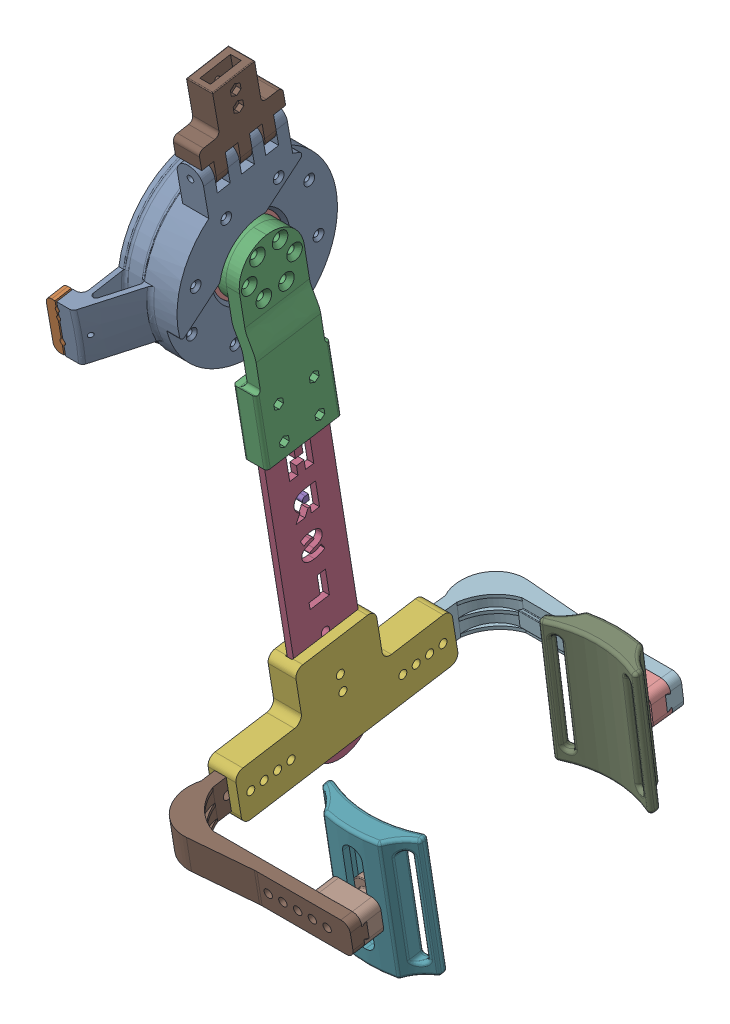
SolidWorks assembly FullExoAssemL_v1, configuration Default. Lengths in mm.
Overall size (178.34 419.53 240.88).
16 component instances, 11 part files, 31 mates.
Components (placement in the parent):
- MotorHousingL_v3-1: MotorHousingL_v3 [Default] at (44.6941 57.478 113.8206) x (0 0.171627 -0.985162) z (1 0 0) size (136.17 126 49)
- RotorAttachCanted_v4_hinge_removed_8mm-1: RotorAttachCanted_v4_hinge_removed_8mm [Default] at (27.6941 57.478 113.8206) x (0 0.15992 -0.98713) z (1 0 0) size (46.2 119 18)
- ThighHinge-1: ThighHinge [Default] at (32.9361 -19.972 124.8736) x (0 -0.113584 -0.993528) z (-0.995056 0.098671 -0.01128) (suppressed, hidden)
- ThighVertAdjust_v1-1: ThighVertAdjust_v1 [Default] at (38.4941 -223.3605 68.3234) x (0 0.15992 -0.98713) z (1 0 0) size (40 225 4)
- ThighTShape_v2-1: ThighTShape_v2 [Default] at (29.6941 -182.6608 75.4235) x (0 0.15992 -0.98713) z (1 0 0) size (134 60 17)
- sliding_mechanism-1: sliding_mechanism [Default] at (171.3989 -236.2303 143.4184) x (-0.99997 0.007656 0.00124) z (0 0.15992 -0.98713) size (60 80 31.83)
  - slide1-2: slide1 [Default] at (35.9132 -9.9128 77.9746) size (60 80 19.04)
  - slide2_centered-2: slide2_centered [Default] at (35.9132 26.7329 3.1866) x (-1 0 0) z (0 0 -1) size (30 20 23)
- sliding_mechanism-2: sliding_mechanism [Default] at (99.5809 -212.8167 -5.0848) x (1 0 0) z (0 -0.122171 0.992509) size (60 80 31.83)
  - slide1-2: slide1 [Default] at (35.9132 -9.9128 77.9746) size (60 80 19.04)
  - slide2_centered-2: slide2_centered [Default] at (35.9132 26.7329 3.1866) x (-1 0 0) z (0 0 -1) size (30 20 23)
- MotorHipAttach-2: MotorHipAttach [Default] at (29.6214 115.3141 117.118) x (0 0 1) z (-0.997763 0.066849 0) (suppressed, hidden)
- Lshape-thigh-3: Lshape-thigh [Default] at (150.6941 -223.7106 172.5083) x (-1 0 0) z (0 0.15992 -0.98713) size (119.06 20 70.06)
- Lshape-thigh-4: Lshape-thigh [Default] at (150.4941 -173.0954 -27.1104) x (-1 0 0) z (0 -0.122171 0.992509) size (119.06 20 70.06)
- AK80-95_-1: AK80-95_ [默认] at (756.7796 -361.1379 390.1752) x (-1 0 0) z (0 -0.550937 -0.834547) size (38.51 98 98)
- Upper_hinge_orthosis_modified-1: Upper_hinge_orthosis_modified [Default] at (28.6941 121.5928 124.5214) x (0 0.171627 -0.985162) z (1 0 0) size (52 53 16)
Mates (geometry in assembly coordinates):
- Concentric1: concentric aligned: cone of MotorHousingL_v3-1 through (26.6941 57.478 113.8206) axis (-1 0 0); cylinder of RotorAttachCanted_v4_hinge_removed_8mm-1 through (33.6941 57.478 113.8206) axis (-1 0 0) radius 20
- Coincident2: coincident anti-aligned: plane of RotorAttachCanted_v2-1 through (36.6214 -11.4544 139.8027) normal (0 -0.113584 -0.993528); plane of ThighHinge-1 through (41.5917 -12.0464 139.8704) normal (0 0.113584 0.993528)
- Concentric2: concentric anti-aligned: circle of RotorAttachCanted_v2-1; circle of ThighHinge-1
- Coincident3: coincident anti-aligned: plane of ThighVertAdjust_v1-1 through (36.4941 -4.4547 124.048) normal (-1 0 0); plane of ThighHinge-1 through (30.051 -24.987 105.0147) normal (0.995056 -0.098671 0.01128)
- Coincident4: coincident anti-aligned: plane of ThighHinge-1 through (32.6382 -22.9378 125.2126) normal (-0.099313 -0.988617 0.113022); plane of ThighVertAdjust_v1-1 through (38.4941 -1.2563 104.3054) normal (0 0.98713 0.15992)
- Coincident5: coincident anti-aligned: plane of ThighHinge-1 through (30.051 -24.987 105.0147) normal (0 0.113584 0.993528); plane of ThighVertAdjust_v1-1 through (36.4941 1.9421 84.5628) normal (0 0.15992 -0.98713)
- Coincident6: coincident anti-aligned: plane of ThighVertAdjust_v1-1 through (36.4941 -4.4547 124.048) normal (-1 0 0); plane of ThighTShape_v2-1 through (36.4941 -215.553 90.8621) normal (1 0 0)
- Coincident8: coincident anti-aligned: plane of MotorHousingL_v3-1 through (20.6941 126.1339 145.0674) normal (0 0.171627 -0.985162); plane of MotorHipAttach-1 through (21.6214 106.3141 135.6369) normal (0 0 1)
- Concentric3: concentric aligned: circle of MotorHousingL_v3-1; circle of MotorHipAttach-1
- Coincident21: coincident anti-aligned: plane of MotorHousingL_v3-1 through (20.6941 126.1339 145.0674) normal (0 0.171627 -0.985162); plane of MotorHipAttach-2 through (37.0019 105.7994 135.6369) normal (0 0 1)
- Concentric6: concentric aligned: circle of MotorHousingL_v3-1; circle of MotorHipAttach-2
- Coincident23: coincident anti-aligned: plane of ThighTShape_v2-1 through (40.6941 -191.5145 98.8086) normal (-1 0 0); plane of Lshape-thigh-3 through (40.6941 -199.6502 149.0542) normal (1 0 0)
- Parallel2: parallel aligned: plane of sliding_mechanism-1/slide2_centered-2 through (150.7344 -207.1727 165.0572) normal (0 -0.15992 0.98713); plane of Lshape-thigh-3 through (150.6941 -203.968 175.7067) normal (0 -0.15992 0.98713)
- Coincident26: coincident anti-aligned: plane of RotorAttachCanted_v4_hinge_removed_8mm-1 through (36.4941 2.4837 84.3466) normal (1 0 0); plane of ThighVertAdjust_v1-1 through (36.4941 -4.4547 124.048) normal (-1 0 0)
- Concentric9: concentric aligned: circle of RotorAttachCanted_v4_hinge_removed_8mm-1; circle of ThighVertAdjust_v1-1
- Concentric13: concentric anti-aligned: circle of RotorAttachCanted_v4_hinge_removed_8mm-1; circle of ThighVertAdjust_v1-1
- Coincident30: coincident anti-aligned: plane of ThighTShape_v2-1 through (33.4941 -183.6784 50.4392) normal (1 0 0); plane of Lshape-thigh-4 through (33.4941 -196.2442 -2.7561) normal (-1 0 0)
- Concentric16: concentric aligned: cylinder of ThighTShape_v2-1 through (24.1941 -189.2757 22.4843) axis (1 0 0) radius 2.45; cylinder of Lshape-thigh-4 through (33.4941 -189.2757 22.4843) axis (1 0 0) radius 2.55
- Coincident36: coincident anti-aligned: plane of sliding_mechanism-2/slide2_centered-2 through (120.4941 -179.0315 -17.7656) normal (0 0.122171 -0.992509); plane of Lshape-thigh-4 through (60.4941 -189.2048 -19.0179) normal (0 -0.122171 0.992509)
- Concentric17: concentric aligned: cylinder of sliding_mechanism-2/slide2_centered-2 through (135.4941 -185.2074 -10.5662) axis (0 0.122171 -0.992509) radius 2.9; cylinder of Lshape-thigh-4 through (135.4941 -184.7309 -14.437) axis (0 0.122171 -0.992509) radius 2.55
- Parallel5: parallel aligned: plane of sliding_mechanism-2/slide2_centered-2 through (150.4941 -173.9384 -20.2621) normal (0 0.992509 0.122171); plane of Lshape-thigh-4 through (60.4941 -176.394 -0.3127) normal (0 0.992509 0.122171)
- Parallel6: parallel anti-aligned: plane of ThighTShape_v2-1 through (33.4941 -191.5145 98.8086) normal (1 0 0); plane of Lshape-thigh-3 through (33.6941 -199.6502 149.0542) normal (-1 0 0)
- Concentric19: concentric anti-aligned: circle of ThighTShape_v2-1; circle of Lshape-thigh-3
- Coincident40: coincident anti-aligned: plane of sliding_mechanism-1/slide2_centered-2 through (150.7344 -207.1727 165.0572) normal (0 -0.15992 0.98713); plane of Lshape-thigh-3 through (60.6941 -207.3045 165.0358) normal (0 0.15992 -0.98713)
- Concentric20: concentric aligned: cylinder of sliding_mechanism-1/slide2_centered-2 through (135.6941 -210.9768 156.4379) axis (0 -0.15992 0.98713) radius 2.9; cylinder of Lshape-thigh-3 through (135.6941 -211.6004 160.2877) axis (0 -0.15992 0.98713) radius 2.55
- Coincident41: coincident anti-aligned: plane of ThighVertAdjust_v1-1 through (36.4941 1.9421 84.5628) normal (0 0.15992 -0.98713); plane of ThighTShape_v2-1 through (36.4941 -208.9963 50.3898) normal (0 -0.15992 0.98713)
- Coincident42: coincident anti-aligned: plane of MotorHousingL_v3-1 through (24.6941 57.478 113.8206) normal (-1 0 0); plane of AK80-95_-1 through (24.6941 77.5071 100.5981) normal (1 0 0)
- Concentric21: concentric aligned: circle of MotorHousingL_v3-1; cylinder of AK80-95_-1 through (13.1941 57.478 113.8206) axis (1 0 0) radius 49
- Concentric22: concentric anti-aligned: cylinder of MotorHousingL_v3-1 through (28.6941 112.4173 177.1899) axis (0 0.171627 -0.985162) radius 2; cylinder of Upper_hinge_orthosis_modified-1 through (28.6941 126.0551 98.9072) axis (0 -0.171627 0.985162) radius 2.1
- Coincident43: coincident anti-aligned: plane of RotorAttachCanted_v4_hinge_removed_8mm-1 through (27.6941 57.478 113.8206) normal (-1 0 0); plane of AK80-95_-1 through (27.6941 72.6667 103.7935) normal (1 0 0)
- Coincident44: coincident aligned: plane of MotorHousingL_v3-1 through (20.6941 117.1094 97.8175) normal (-1 0 0); plane of Upper_hinge_orthosis_modified-1 through (20.6941 126.0551 98.9072) normal (-1 0 0)
